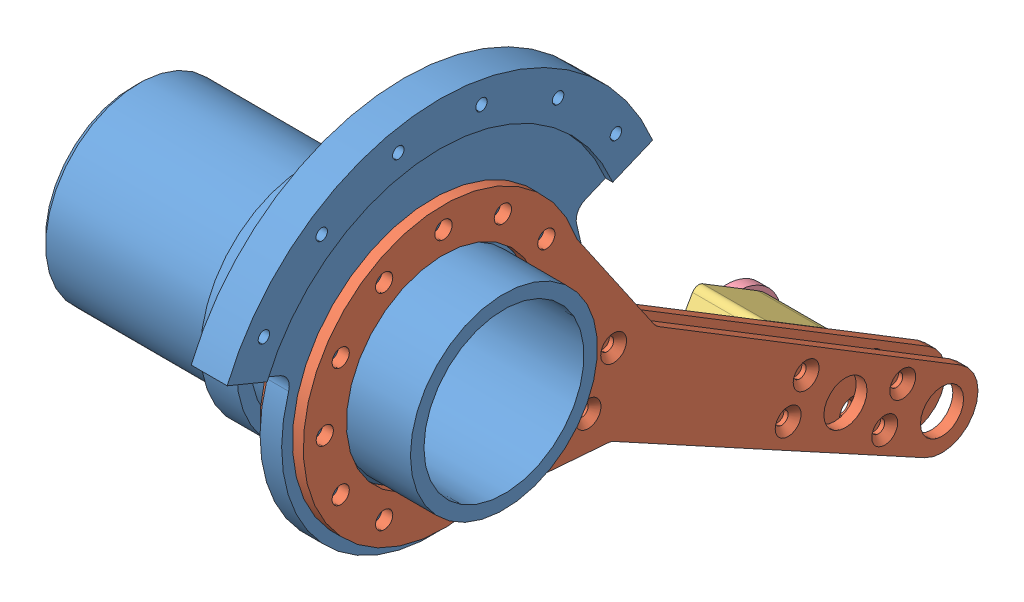
SolidWorks assembly hip-hind-new-right-2012-09-05, configuration Default. Lengths in mm.
Overall size (51.7 109 118.28).
7 component instances, 6 part files, 17 mates.
Components (placement in the parent):
- abs-hip-front-2012-11-20-1: abs-hip-front-2012-11-20 [Default] at (15.6334 7.6716 -13.4615) size (51.7 53 129.22)
- Hip_gear-1: Hip_gear [Default] at (14.6334 7.6716 -13.4615) x (1 0 0) z (0 -0.382683 -0.92388) size (9 71.48 71.48)
- carbon-plate-hip-hind-1: carbon-plate-hip-hind [Default] at (12.6334 7.6716 -13.4615) x (0 -0.5 -0.866025) z (1 0 0) size (106 42 1.5)
- carbon-plate-hip-hind-2: carbon-plate-hip-hind [Default] at (17.1334 7.6716 -13.4615) x (0 -0.5 -0.866025) z (1 0 0) size (106 42 1.5)
- Pom-plat-hip-hind-04-03-13-1: Pom-plat-hip-hind-04-03-13 [Default] at (14.1334 7.6716 -13.4615) x (0 -0.5 -0.866025) z (1 0 0) size (68.27 23.38 3)
- distancepiece_legsprings_011112_Mill_Pom-1: distancepiece_legsprings_011112_Mill_Pom [Default] at (8.1834 -24.5784 -69.3201) x (0 -0.866025 0.5) z (-1 0 0) size (11.24 15.4 8.9)
- Washer-d6p5-12-1: Washer-d6p5-12 [Défaut] at (2.9334 -24.5784 -69.3201) x (0 0 -1) z (1 0 0) size (12 12 1.6)
Mates (geometry in assembly coordinates):
- Concentric1: concentric anti-aligned: cylinder of abs-hip-front-2012-11-20-1 through (15.6334 7.6716 -13.4615) axis (-1 0 0) radius 32; cylinder of Hip_gear-1 through (13.1334 7.6716 -13.4615) axis (1 0 0) radius 32
- Coincident1: coincident anti-aligned: plane of abs-hip-front-2012-11-20-1 through (13.1334 19.9175 16.1027) normal (-1 0 0); plane of Hip_gear-1 through (13.1334 31.6925 -23.4113) normal (1 0 0)
- Coincident2: coincident anti-aligned: plane of abs-hip-front-2012-11-20-1 through (14.1334 12.6465 -1.4511) normal (-1 0 0); plane of carbon-plate-hip-hind-1 through (14.1334 -32.3284 -82.7435) normal (1 0 0)
- Concentric3: concentric aligned: cylinder of abs-hip-front-2012-11-20-1 through (15.6334 7.6716 -13.4615) axis (-1 0 0) radius 21; cylinder of carbon-plate-hip-hind-1 through (14.1334 7.6716 -13.4615) axis (-1 0 0) radius 15.1
- Concentric4: concentric aligned: cylinder of abs-hip-front-2012-11-20-1 through (15.6334 7.6716 -13.4615) axis (-1 0 0) radius 13; cylinder of carbon-plate-hip-hind-2 through (18.6334 7.6716 -13.4615) axis (-1 0 0) radius 15.1
- Coincident3: coincident anti-aligned: plane of abs-hip-front-2012-11-20-1 through (17.1334 12.6465 -1.4511) normal (1 0 0); plane of carbon-plate-hip-hind-2 through (17.1334 -32.3284 -82.7435) normal (-1 0 0)
- Concentric5: concentric aligned: cylinder of carbon-plate-hip-hind-1 through (14.1334 -32.3284 -82.7435) axis (-1 0 0) radius 3; cylinder of carbon-plate-hip-hind-2 through (18.6334 -32.3284 -82.7435) axis (-1 0 0) radius 3
- Coincident4: coincident anti-aligned: plane of Pom-plat-hip-hind-04-03-13-1 through (17.1334 -32.3284 -82.7435) normal (1 0 0); plane of carbon-plate-hip-hind-2 through (17.1334 -32.3284 -82.7435) normal (-1 0 0)
- Concentric6: concentric aligned: cylinder of carbon-plate-hip-hind-2 through (18.6334 -24.5784 -69.3201) axis (-1 0 0) radius 3; cylinder of Pom-plat-hip-hind-04-03-13-1 through (17.1334 -24.5784 -69.3201) axis (-1 0 0) radius 3
- Concentric7: concentric aligned: cylinder of carbon-plate-hip-hind-2 through (18.6334 -32.3284 -82.7435) axis (-1 0 0) radius 3; cylinder of Pom-plat-hip-hind-04-03-13-1 through (17.1334 -32.3284 -82.7435) axis (-1 0 0) radius 3
- Concentric8: concentric anti-aligned: cylinder of abs-hip-front-2012-11-20-1 through (17.1334 23.2533 10.9969) axis (1 0 0) radius 0.8; cylinder of Hip_gear-1 through (10.1334 23.2533 10.9969) axis (-1 0 0) radius 1.2
- Concentric11: concentric anti-aligned: cylinder of abs-hip-front-2012-11-20-1 through (14.1334 16.4216 -28.6169) axis (-1 0 0) radius 0.625; cylinder of carbon-plate-hip-hind-1 through (14.1334 16.4216 -28.6169) axis (1 0 0) radius 0.9
- Coïncidente1: coincident anti-aligned: plane of carbon-plate-hip-hind-1 through (12.6334 -32.3284 -82.7435) normal (-1 0 0); plane of distancepiece_legsprings_011112_Mill_Pom-1 through (12.6334 -24.5784 -69.3201) normal (1 0 0)
- Coaxiale1: concentric aligned: cylinder of Pom-plat-hip-hind-04-03-13-1 through (17.1334 -22.8685 -61.3584) axis (1 0 0) radius 0.625; cylinder of distancepiece_legsprings_011112_Mill_Pom-1 through (12.6334 -22.8685 -61.3584) axis (1 0 0) radius 0.625
- Coaxiale2: concentric aligned: cylinder of Pom-plat-hip-hind-04-03-13-1 through (17.1334 -18.5383 -63.8584) axis (1 0 0) radius 0.625; cylinder of distancepiece_legsprings_011112_Mill_Pom-1 through (12.6334 -18.5383 -63.8584) axis (1 0 0) radius 0.625
- Coïncidente2: coincident anti-aligned: plane of distancepiece_legsprings_011112_Mill_Pom-1 through (3.7334 -24.5784 -69.3201) normal (-1 0 0); plane of Washer-d6p5-12-1 through (3.7334 -24.5784 -69.3201) normal (1 0 0)
- Coaxiale3: concentric aligned: cylinder of distancepiece_legsprings_011112_Mill_Pom-1 through (12.6334 -24.5784 -69.3201) axis (-1 0 0) radius 3.05; cylinder of Washer-d6p5-12-1 through (3.7334 -24.5784 -69.3201) axis (-1 0 0) radius 3.25
